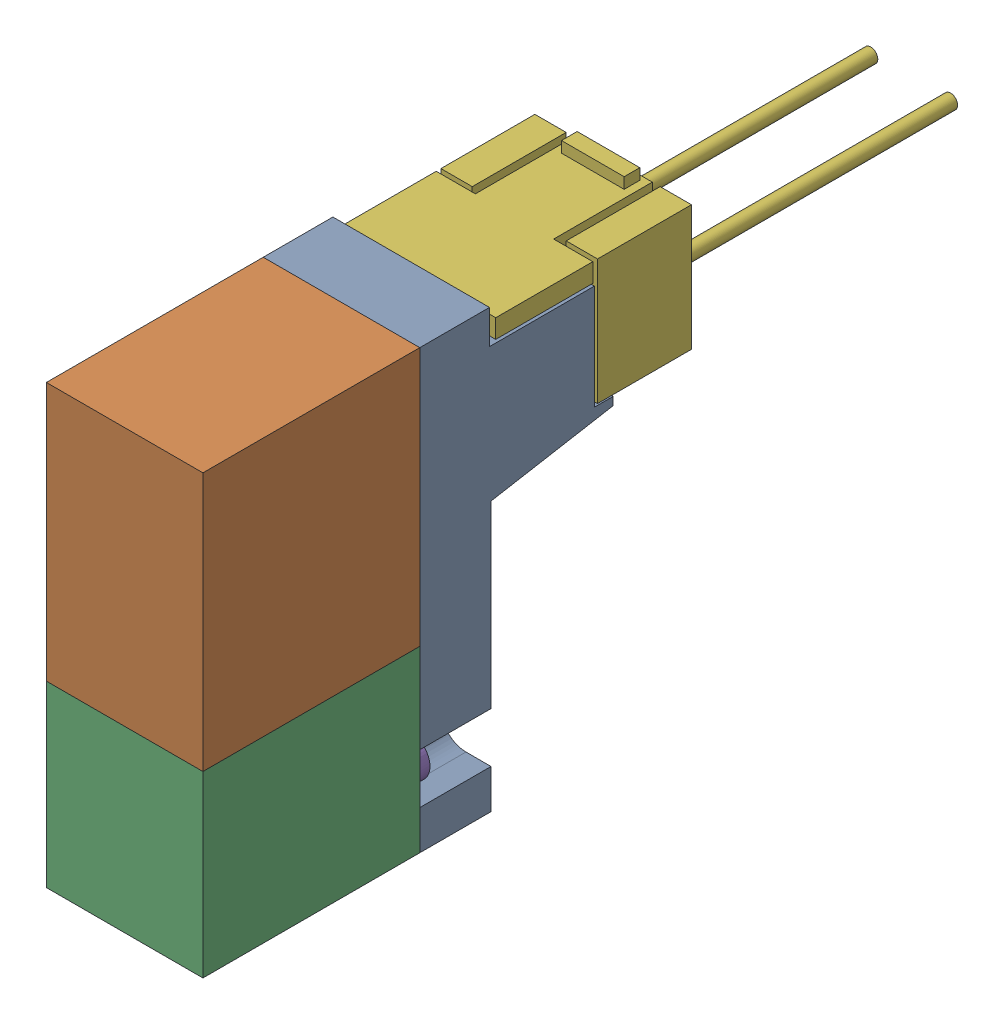
SolidWorks assembly 4GA120-M5-E01-4_D_100000_4G-Coil-SubASSY_01(EDC-E-H), configuration Default. Lengths in mm.
Overall size (10 27.94 50.2).
2 component instances, 2 part files, 0 mates.
Components (placement in the parent):
- 4GA120-M5-E01-4_D_000102_4GcoilEDC_00(Default)-1: 4GA120-M5-E01-4_D_000102_4GcoilEDC_00(Default) [Default] at origin size (10 27.94 26.2)
- 4GA120-M5-E01-4_D_000123_4GSocketAssyE_00(Default)-1: 4GA120-M5-E01-4_D_000123_4GSocketAssyE_00(Default) [Default] at (0 22.17 -25.2) size (10 8.7 31.5)
